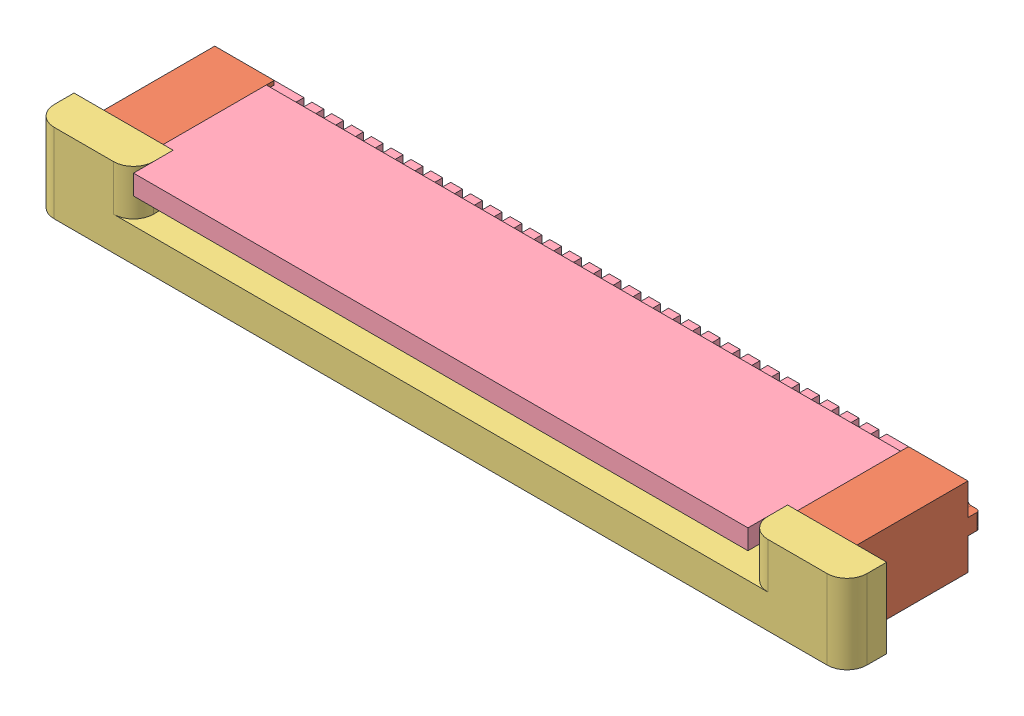
SolidWorks assembly 20436_ACF-050-30-C-CMS-H, configuration Standard. Lengths in mm.
Overall size (20.5 2 5).
36 component instances, 4 part files, 0 mates.
Components (placement in the parent):
- 20436_ACF-050-30-C-CMS-H.stp-1: 20436_ACF-050-30-C-CMS-H.stp [Standard] at origin size (20.5 2 5)
  - ANTELEC-FFC-P281-C-1R.stp-1: ANTELEC-FFC-P281-C-1R.stp [Standard] at origin size (20.5 2 5)
    - Broche P281 H.stp-1: Broche P281 H.stp [Standard] at (14.75 1 1.3) x (0 -1 0) z (-1 0 0) size (2 4.79 0.2)
    - Broche P281 H.stp-2: Broche P281 H.stp [Standard] at (4.25 1 1.3) x (0 -1 0) z (-1 0 0) size (2 4.79 0.2)
    - Broche P281 H.stp-3: Broche P281 H.stp [Standard] at (15.25 1 1.3) x (0 -1 0) z (-1 0 0) size (2 4.79 0.2)
    - Broche P281 H.stp-4: Broche P281 H.stp [Standard] at (3.75 1 1.3) x (0 -1 0) z (-1 0 0) size (2 4.79 0.2)
    - Broche P281 H.stp-5: Broche P281 H.stp [Standard] at (15.75 1 1.3) x (0 -1 0) z (-1 0 0) size (2 4.79 0.2)
    - Broche P281 H.stp-6: Broche P281 H.stp [Standard] at (3.25 1 1.3) x (0 -1 0) z (-1 0 0) size (2 4.79 0.2)
    - Broche P281 H.stp-7: Broche P281 H.stp [Standard] at (9.75 1 1.3) x (0 -1 0) z (-1 0 0) size (2 4.79 0.2)
    - Broche P281 H.stp-8: Broche P281 H.stp [Standard] at (9.25 1 1.3) x (0 -1 0) z (-1 0 0) size (2 4.79 0.2)
    - Broche P281 H.stp-9: Broche P281 H.stp [Standard] at (10.25 1 1.3) x (0 -1 0) z (-1 0 0) size (2 4.79 0.2)
    - Broche P281 H.stp-10: Broche P281 H.stp [Standard] at (8.75 1 1.3) x (0 -1 0) z (-1 0 0) size (2 4.79 0.2)
    - Broche P281 H.stp-11: Broche P281 H.stp [Standard] at (10.75 1 1.3) x (0 -1 0) z (-1 0 0) size (2 4.79 0.2)
    - Broche P281 H.stp-12: Broche P281 H.stp [Standard] at (8.25 1 1.3) x (0 -1 0) z (-1 0 0) size (2 4.79 0.2)
    - Broche P281 H.stp-13: Broche P281 H.stp [Standard] at (11.25 1 1.3) x (0 -1 0) z (-1 0 0) size (2 4.79 0.2)
    - Broche P281 H.stp-14: Broche P281 H.stp [Standard] at (7.75 1 1.3) x (0 -1 0) z (-1 0 0) size (2 4.79 0.2)
    - Broche P281 H.stp-15: Broche P281 H.stp [Standard] at (11.75 1 1.3) x (0 -1 0) z (-1 0 0) size (2 4.79 0.2)
    - Broche P281 H.stp-16: Broche P281 H.stp [Standard] at (7.25 1 1.3) x (0 -1 0) z (-1 0 0) size (2 4.79 0.2)
    - Broche P281 H.stp-17: Broche P281 H.stp [Standard] at (12.25 1 1.3) x (0 -1 0) z (-1 0 0) size (2 4.79 0.2)
    - Broche P281 H.stp-18: Broche P281 H.stp [Standard] at (6.75 1 1.3) x (0 -1 0) z (-1 0 0) size (2 4.79 0.2)
    - Broche P281 H.stp-19: Broche P281 H.stp [Standard] at (12.75 1 1.3) x (0 -1 0) z (-1 0 0) size (2 4.79 0.2)
    - Broche P281 H.stp-20: Broche P281 H.stp [Standard] at (6.25 1 1.3) x (0 -1 0) z (-1 0 0) size (2 4.79 0.2)
    - Broche P281 H.stp-21: Broche P281 H.stp [Standard] at (13.25 1 1.3) x (0 -1 0) z (-1 0 0) size (2 4.79 0.2)
    - Broche P281 H.stp-22: Broche P281 H.stp [Standard] at (5.75 1 1.3) x (0 -1 0) z (-1 0 0) size (2 4.79 0.2)
    - Broche P281 H.stp-23: Broche P281 H.stp [Standard] at (13.75 1 1.3) x (0 -1 0) z (-1 0 0) size (2 4.79 0.2)
    - Broche P281 H.stp-24: Broche P281 H.stp [Standard] at (5.25 1 1.3) x (0 -1 0) z (-1 0 0) size (2 4.79 0.2)
    - Broche P281 H.stp-25: Broche P281 H.stp [Standard] at (14.25 1 1.3) x (0 -1 0) z (-1 0 0) size (2 4.79 0.2)
    - Broche P281 H.stp-26: Broche P281 H.stp [Standard] at (4.75 1 1.3) x (0 -1 0) z (-1 0 0) size (2 4.79 0.2)
    - Broche P281 H.stp-27: Broche P281 H.stp [Standard] at (16.25 1 1.3) x (0 -1 0) z (-1 0 0) size (2 4.79 0.2)
    - Broche P281 H.stp-28: Broche P281 H.stp [Standard] at (2.75 1 1.3) x (0 -1 0) z (-1 0 0) size (2 4.79 0.2)
    - Broche P281 H.stp-29: Broche P281 H.stp [Standard] at (16.75 1 1.3) x (0 -1 0) z (-1 0 0) size (2 4.79 0.2)
    - Broche P281 H.stp-30: Broche P281 H.stp [Standard] at (2.25 1 1.3) x (0 -1 0) z (-1 0 0) size (2 4.79 0.2)
    - Partie métallique P281.stp-1: Partie métallique P281.stp [Standard] at (18 1 -0.2) x (0 -1 0) z (0 0 1) size (2 1.8 3.1)
    - Partie métallique P281.stp-2: Partie métallique P281.stp [Standard] at (0.8 1 -0.2) x (0 1 0) z (0 0 1) size (2 1.8 3.1)
    - Capot P281-C-1R.stp-1: Capot P281-C-1R.stp [Standard] at (9.4 1 0.9) x (-1 0 0) z (0 0 1) size (20.5 2 3)
    - Isolant P281-C-1R.stp-1: Isolant P281-C-1R.stp [Standard] at (9.4 1 0) size (18.8 2 3.9)
